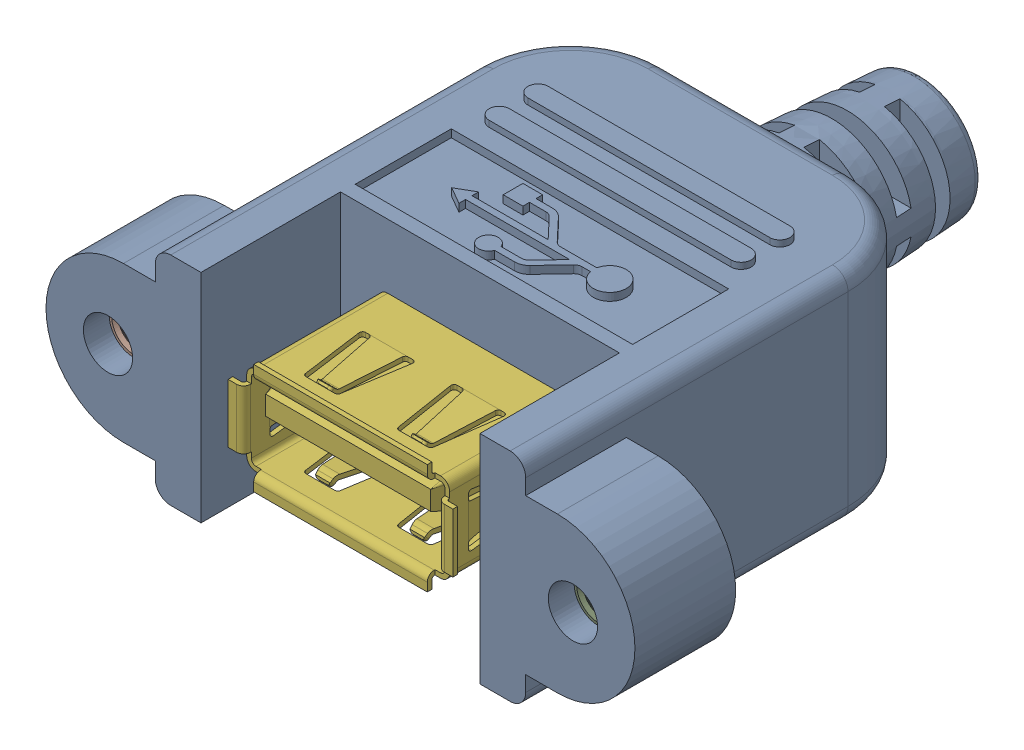
SolidWorks assembly MTN-157_NEW LOGO, configuration Default. Lengths in mm.
Overall size (38 14.8 37.5).
6 component instances, 4 part files, 0 mates.
Components (placement in the parent):
- MTN-157_NEW L-COM LOGO-1: MTN-157_NEW L-COM LOGO [Default] at origin size (38 14.8 37.5)
- MTN-268-1: MTN-268 [Default] at (0 0 -11.684) x (-1 0 0) z (0 0 1) size (19.05 9.91 24.89)
  - MTN-268-1: MTN-268 [Default] at origin size (19.05 9.91 13.21)
  - 1AA05-008(USB A TYPE FEMALE SOLDER TYPE)-1: 1AA05-008(USB A TYPE FEMALE SOLDER TYPE) [Default] at (0 0 -2.616) x (-1 0 0) z (0 0 1) size (14.5 7.12 17.8)
- STKB-440-4-1: STKB-440-4 [Default] at (-15 0 -4.8375) size (4.78 4.78 3.17)
- STKB-440-4-2: STKB-440-4 [Default] at (15 0 -4.8375) size (4.78 4.78 3.17)
